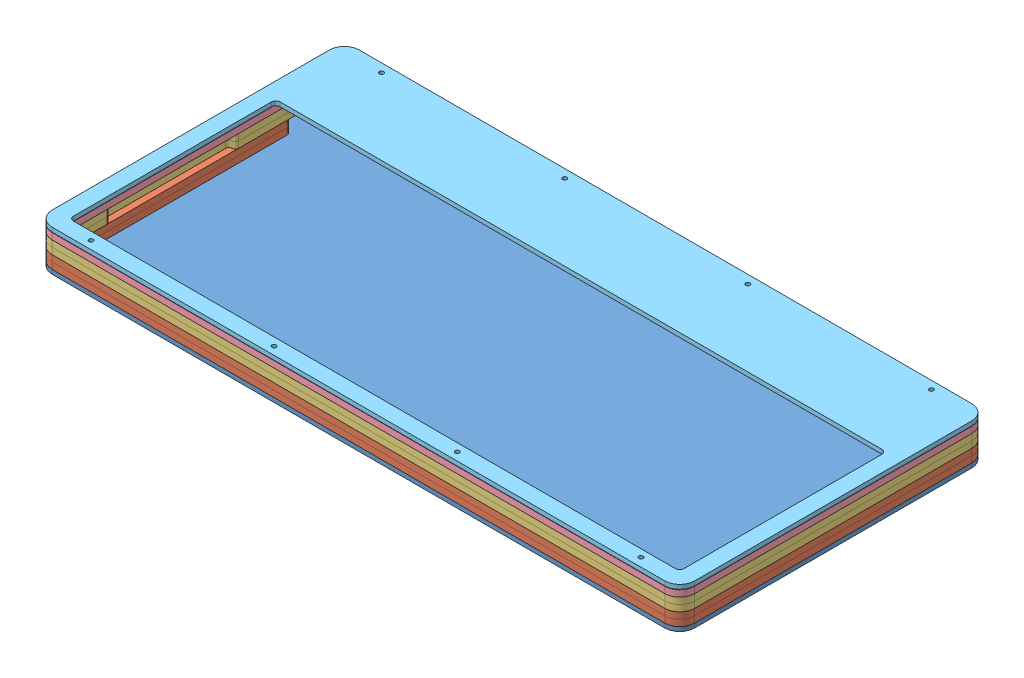
SolidWorks assembly Assem1, configuration Default. Lengths in mm.
Overall size (301.7 19.18 144.2).
7 component instances, 5 part files, 7 mates.
Components (placement in the parent):
- bottom_2mm-3: bottom_2mm [Default] at (-43.1764 265.3669 186.8003) size (301.7 2 144.2)
- usb_cutout_3mm-3: usb_cutout_3mm [Default] at (-56.4374 267.3669 142.5513) size (301.7 3 144.2)
- usb_cutout_3mm-4: usb_cutout_3mm [Default] at (-56.4374 270.3669 142.5513) size (301.7 3 144.2)
- gasket_layer_3mm-3: gasket_layer_3mm [Default] at (-28.4646 273.3669 125.7481) size (301.7 3 144.2)
- gasket_layer_3mm-4: gasket_layer_3mm [Default] at (-28.4646 276.3669 125.7481) size (301.7 3 144.2)
- middle_3mm-3: middle_3mm [Default] at (-40.4675 279.3669 150.7003) size (301.7 3 144.2)
- top_2mm-3: top_2mm [Default] at (-37.3053 282.544 152.2912) size (301.7 2 144.2)
Mates (geometry in assembly coordinates):
- Coincident5: coincident anti-aligned: circle of bottom_2mm-3; circle of usb_cutout_3mm-3
- Coincident6: coincident anti-aligned: plane of usb_cutout_3mm-3 through (-56.4374 270.3669 142.5513) normal (0 1 0); plane of usb_cutout_3mm-4 through (-56.4374 270.3669 142.5513) normal (0 -1 0)
- Coincident7: coincident aligned: cylinder of usb_cutout_3mm-3; cylinder of usb_cutout_3mm-4 through (262.8171 263.3669 116.0539) axis (0 1 0) radius 1.7
- Coincident8: coincident aligned: circle of usb_cutout_3mm-4; circle of gasket_layer_3mm-3
- Coincident9: coincident aligned: circle of gasket_layer_3mm-3; circle of gasket_layer_3mm-4
- Coincident10: coincident anti-aligned: circle of gasket_layer_3mm-4; circle of middle_3mm-3
- Concentric1: concentric anti-aligned: circle of middle_3mm-3; circle of top_2mm-3
